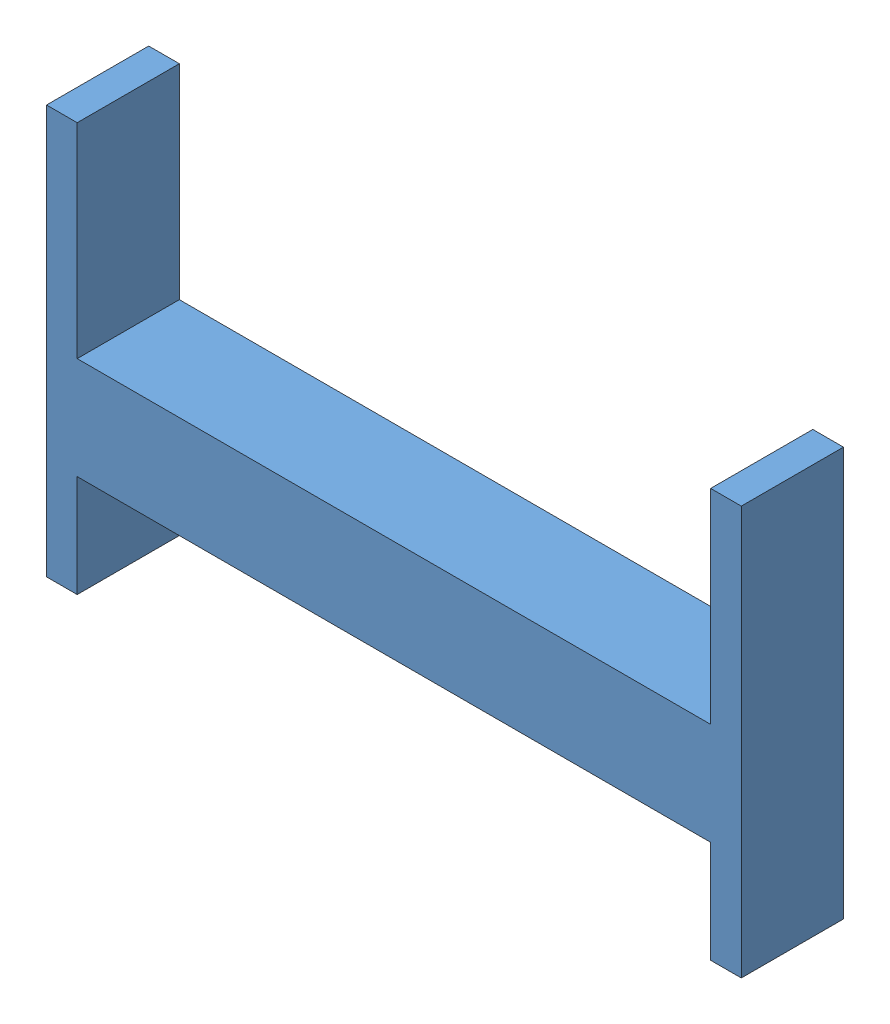
SolidWorks assembly Estante armado, configuration Predeterminado. Lengths in mm.
Overall size (340 200 50).
86 component instances, 6 part files, 9 mates.
Components (placement in the parent):
- Estante-1: Estante [Predeterminado] at (-139.594 -89.0513 3500) (suppressed, hidden)
- Cajon-1: Cajon [Predeterminado] at (-1679.594 1400.9487 3497.5428) (suppressed, hidden)
- Cajon-2: Cajon [Predeterminado] at (-1679.594 1015.9487 3497.5428) (suppressed, hidden)
- Cajon-3: Cajon [Predeterminado] at (-1679.594 630.9487 3497.5428) (suppressed, hidden)
- Cajon-4: Cajon [Predeterminado] at (-1679.594 245.9487 3497.5428) (suppressed, hidden)
- Cajon-5: Cajon [Predeterminado] at (-1679.594 -139.0513 3497.5428) (suppressed, hidden)
- Cajon-6: Cajon [Predeterminado] at (-1679.594 -524.0513 3497.5428) (suppressed, hidden)
- Cajon-7: Cajon [Predeterminado] at (-1679.594 -909.0513 3497.5428) (suppressed, hidden)
- Cajon-8: Cajon [Predeterminado] at (-1679.594 -1294.0513 3497.5428) (suppressed, hidden)
- Cajon-9: Cajon [Predeterminado] at (-1679.594 -1679.0513 3497.5428) (suppressed, hidden)
- Cajon-10: Cajon [Predeterminado] at (-1294.594 1400.9487 3497.5428) (suppressed, hidden)
- Cajon-11: Cajon [Predeterminado] at (-1294.594 1015.9487 3497.5428) (suppressed, hidden)
- Cajon-12: Cajon [Predeterminado] at (-1294.594 630.9487 3497.5428) (suppressed, hidden)
- Cajon-13: Cajon [Predeterminado] at (-1294.594 245.9487 3497.5428) (suppressed, hidden)
- Cajon-14: Cajon [Predeterminado] at (-1294.594 -139.0513 3497.5428) (suppressed, hidden)
- Cajon-15: Cajon [Predeterminado] at (-1294.594 -524.0513 3497.5428) (suppressed, hidden)
- Cajon-16: Cajon [Predeterminado] at (-1294.594 -909.0513 3497.5428) (suppressed, hidden)
- Cajon-17: Cajon [Predeterminado] at (-1294.594 -1294.0513 3497.5428) (suppressed, hidden)
- Cajon-18: Cajon [Predeterminado] at (-1294.594 -1679.0513 3497.5428) (suppressed, hidden)
- Cajon-19: Cajon [Predeterminado] at (-909.594 1400.9487 3497.5428) (suppressed, hidden)
- Cajon-20: Cajon [Predeterminado] at (-909.594 1015.9487 3497.5428) (suppressed, hidden)
- Cajon-21: Cajon [Predeterminado] at (-909.594 630.9487 3497.5428) (suppressed, hidden)
- Cajon-22: Cajon [Predeterminado] at (-909.594 245.9487 3497.5428) (suppressed, hidden)
- Cajon-23: Cajon [Predeterminado] at (-909.594 -139.0513 3497.5428) (suppressed, hidden)
- Cajon-24: Cajon [Predeterminado] at (-909.594 -524.0513 3497.5428) (suppressed, hidden)
- Cajon-25: Cajon [Predeterminado] at (-909.594 -909.0513 3497.5428) (suppressed, hidden)
- Cajon-26: Cajon [Predeterminado] at (-909.594 -1294.0513 3497.5428) (suppressed, hidden)
- Cajon-27: Cajon [Predeterminado] at (-909.594 -1679.0513 3497.5428) (suppressed, hidden)
- Cajon-28: Cajon [Predeterminado] at (-524.594 1400.9487 3497.5428) (suppressed, hidden)
- Cajon-29: Cajon [Predeterminado] at (-524.594 1015.9487 3497.5428) (suppressed, hidden)
- Cajon-30: Cajon [Predeterminado] at (-524.594 630.9487 3497.5428) (suppressed, hidden)
- Cajon-31: Cajon [Predeterminado] at (-524.594 245.9487 3497.5428) (suppressed, hidden)
- Cajon-32: Cajon [Predeterminado] at (-524.594 -139.0513 3497.5428) (suppressed, hidden)
- Cajon-33: Cajon [Predeterminado] at (-524.594 -524.0513 3497.5428) (suppressed, hidden)
- Cajon-34: Cajon [Predeterminado] at (-524.594 -909.0513 3497.5428) (suppressed, hidden)
- Cajon-35: Cajon [Predeterminado] at (-524.594 -1294.0513 3497.5428) (suppressed, hidden)
- Cajon-36: Cajon [Predeterminado] at (-524.594 -1679.0513 3497.5428) (suppressed, hidden)
- Cajon-37: Cajon [Predeterminado] at (-139.594 1400.9487 3497.5428) (suppressed, hidden)
- Cajon-38: Cajon [Predeterminado] at (-139.594 1015.9487 3497.5428) (suppressed, hidden)
- Cajon-39: Cajon [Predeterminado] at (-139.594 630.9487 3497.5428) (suppressed, hidden)
- Cajon-40: Cajon [Predeterminado] at (-139.594 245.9487 3497.5428) (suppressed, hidden)
- Cajon-41: Cajon [Predeterminado] at (-139.594 -139.0513 3497.5428) (suppressed, hidden)
- Cajon-42: Cajon [Predeterminado] at (-139.594 -524.0513 3497.5428) (suppressed, hidden)
- Cajon-43: Cajon [Predeterminado] at (-139.594 -909.0513 3497.5428) (suppressed, hidden)
- Cajon-44: Cajon [Predeterminado] at (-139.594 -1294.0513 3497.5428) (suppressed, hidden)
- Cajon-45: Cajon [Predeterminado] at (-139.594 -1679.0513 3497.5428) (suppressed, hidden)
- Cajon-46: Cajon [Predeterminado] at (245.406 1400.9487 3497.5428) (suppressed, hidden)
- Cajon-47: Cajon [Predeterminado] at (245.406 1015.9487 3497.5428) (suppressed, hidden)
- Cajon-48: Cajon [Predeterminado] at (245.406 630.9487 3497.5428) (suppressed, hidden)
- Cajon-49: Cajon [Predeterminado] at (245.406 245.9487 3497.5428) (suppressed, hidden)
- Cajon-50: Cajon [Predeterminado] at (245.406 -139.0513 3497.5428) (suppressed, hidden)
- Cajon-51: Cajon [Predeterminado] at (245.406 -524.0513 3497.5428) (suppressed, hidden)
- Cajon-52: Cajon [Predeterminado] at (245.406 -909.0513 3497.5428) (suppressed, hidden)
- Cajon-53: Cajon [Predeterminado] at (245.406 -1294.0513 3497.5428) (suppressed, hidden)
- Cajon-54: Cajon [Predeterminado] at (245.406 -1679.0513 3497.5428) (suppressed, hidden)
- Cajon-55: Cajon [Predeterminado] at (630.406 1400.9487 3497.5428) (suppressed, hidden)
- Cajon-56: Cajon [Predeterminado] at (630.406 1015.9487 3497.5428) (suppressed, hidden)
- Cajon-57: Cajon [Predeterminado] at (630.406 630.9487 3497.5428) (suppressed, hidden)
- Cajon-58: Cajon [Predeterminado] at (630.406 245.9487 3497.5428) (suppressed, hidden)
- Cajon-59: Cajon [Predeterminado] at (630.406 -139.0513 3497.5428) (suppressed, hidden)
- Cajon-60: Cajon [Predeterminado] at (630.406 -524.0513 3497.5428) (suppressed, hidden)
- Cajon-61: Cajon [Predeterminado] at (630.406 -909.0513 3497.5428) (suppressed, hidden)
- Cajon-62: Cajon [Predeterminado] at (630.406 -1294.0513 3497.5428) (suppressed, hidden)
- Cajon-63: Cajon [Predeterminado] at (630.406 -1679.0513 3497.5428) (suppressed, hidden)
- Cajon-64: Cajon [Predeterminado] at (1015.406 1400.9487 3497.5428) (suppressed, hidden)
- Cajon-65: Cajon [Predeterminado] at (1015.406 1015.9487 3497.5428) (suppressed, hidden)
- Cajon-66: Cajon [Predeterminado] at (1015.406 630.9487 3497.5428) (suppressed, hidden)
- Cajon-67: Cajon [Predeterminado] at (1015.406 245.9487 3497.5428) (suppressed, hidden)
- Cajon-68: Cajon [Predeterminado] at (1015.406 -139.0513 3497.5428) (suppressed, hidden)
- Cajon-69: Cajon [Predeterminado] at (1015.406 -524.0513 3497.5428) (suppressed, hidden)
- Cajon-70: Cajon [Predeterminado] at (1015.406 -909.0513 3497.5428) (suppressed, hidden)
- Cajon-71: Cajon [Predeterminado] at (1015.406 -1294.0513 3497.5428) (suppressed, hidden)
- Cajon-72: Cajon [Predeterminado] at (1015.406 -1679.0513 3497.5428) (suppressed, hidden)
- Cajon-73: Cajon [Predeterminado] at (1400.406 1400.9487 3497.5428) (suppressed, hidden)
- Cajon-74: Cajon [Predeterminado] at (1400.406 1015.9487 3497.5428) (suppressed, hidden)
- Cajon-75: Cajon [Predeterminado] at (1400.406 630.9487 3497.5428) (suppressed, hidden)
- Cajon-76: Cajon [Predeterminado] at (1400.406 245.9487 3497.5428) (suppressed, hidden)
- Cajon-77: Cajon [Predeterminado] at (1400.406 -139.0513 3497.5428) (suppressed, hidden)
- Cajon-78: Cajon [Predeterminado] at (1400.406 -524.0513 3497.5428) (suppressed, hidden)
- Cajon-79: Cajon [Predeterminado] at (1400.406 -909.0513 3497.5428) (suppressed, hidden)
- Cajon-80: Cajon [Predeterminado] at (1400.406 -1294.0513 3497.5428) (suppressed, hidden)
- Cajon-81: Cajon [Predeterminado] at (1400.406 -1679.0513 3497.5428) (suppressed, hidden)
- ejeX-1: ejeX [Predeterminado] at (-139.594 -2054.0513 4200) (suppressed, hidden)
- ejeZ-1: ejeZ [Predeterminado] at (1077.9898 -246.5513 4000) x (0 1 0) z (0 0 1) (suppressed, hidden)
- baseRob-1: baseRob [Predeterminado] at (1094.2326 -1954.0513 4340) (suppressed, hidden)
- Efector-1: Efector [Predeterminado] at (-177.2718 -2257.1201 4453.056) size (340 200 50)
Mates (geometry in assembly coordinates):
- Coincidente1: coincident anti-aligned: plane of Estante-1 through (-1504.594 1400.9487 4000) normal (-1 0 0); plane of Cajon-1 through (-1504.594 1400.9487 3497.5428) normal (1 0 0)
- Coincidente2: coincident anti-aligned: plane of Estante-1 through (-1854.594 1275.9487 4000) normal (0 1 0); plane of Cajon-1 through (-1529.594 1275.9487 3997.5428) normal (0 -1 0)
- Coincidente6: coincident aligned: plane of Estante-1 through (-1889.594 -2154.0513 4000) normal (0 -1 0); plane of ejeX-1 through (1610.406 -2154.0513 4400) normal (0 -1 0)
- Coincidente7: coincident anti-aligned: plane of Estante-1 through (1610.406 -1839.0513 4000) normal (1 0 0); plane of ejeX-1 through (1610.406 -2054.0513 4200) normal (-1 0 0)
- Coincidente9: coincident aligned: plane of ejeX-1 through (1610.406 -2154.0513 4400) normal (0 -1 0); plane of ejeZ-1 through (1177.9898 -2154.0513 4200) normal (0 -1 0)
- Coincidente13: coincident anti-aligned: plane of Estante-1 through (-139.594 -89.0513 4000) normal (0 0 1); plane of ejeZ-1 through (1077.9898 -246.5513 4000) normal (0 0 -1)
- Coincidente14: coincident aligned: plane of Estante-1 through (-139.594 -89.0513 3500) normal (0 0 -1); plane of ejeX-1 through (1710.406 -2154.0513 3500) normal (0 0 -1)
- Coincidente15: coincident anti-aligned: plane of ejeX-1 through (1610.406 -1954.0513 4400) normal (0 1 0); plane of baseRob-1 through (1094.2326 -1954.0513 4340) normal (0 -1 0)
- Coincidente16: coincident anti-aligned: plane of ejeZ-1 through (1077.9898 -246.5513 4200) normal (0 0 1); plane of baseRob-1 through (979.2326 -1804.0513 4200) normal (0 0 -1)
